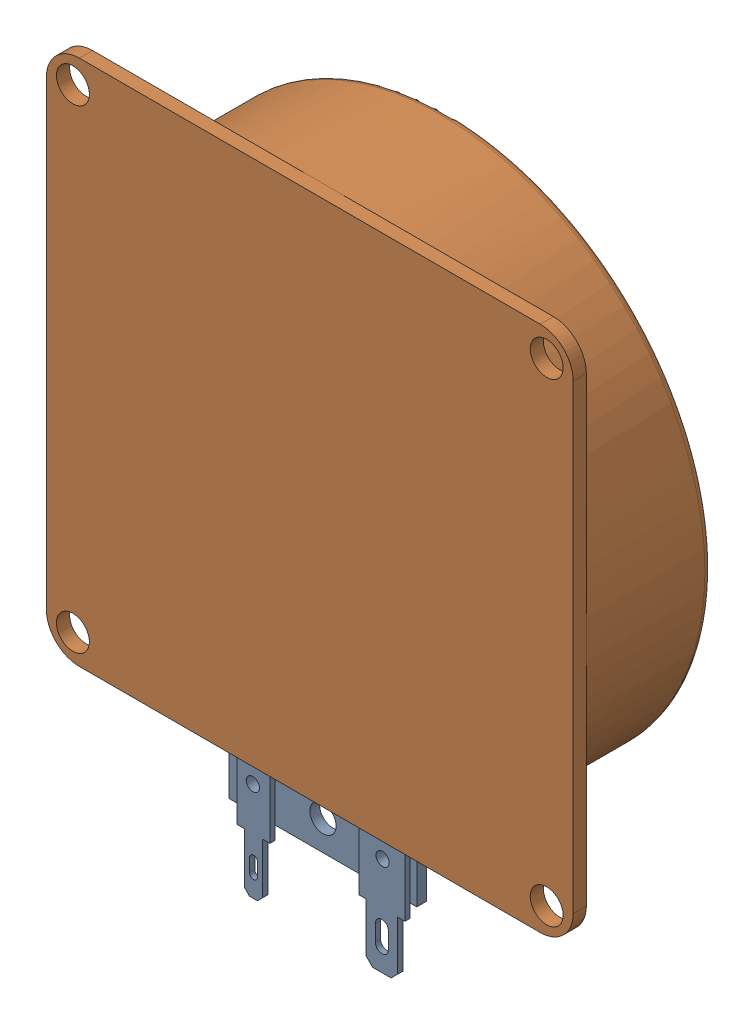
SolidWorks assembly EX 80 S, configuration Défaut. Lengths in mm.
Overall size (80 98.5 23).
2 component instances, 2 part files, 2 mates.
Components (placement in the parent):
- Fiche_Visaton_EX_80_S-1: Fiche_Visaton_EX_80_S [Défaut] at (41.1786 -10.9273 998.85) size (28.5 19.5 2.3)
- Visaton_EX_80_S-1: Visaton_EX_80_S [Défaut] at (-20.9808 65.6054 1002.35) x (-1 0 0) z (0 0 -1) size (80 80 23)
Mates (geometry in assembly coordinates):
- Coïncidente15: coincident: plane of Fiche_Visaton_EX_80_S-1 through (41.1786 19.3897 1001.15) normal (0 1 0); plane of Visaton_EX_80_S-1 through (16.7362 19.3897 1000.35) normal (0 -1 0)
- Distance2: distance = 25.75 mm aligned: plane of Fiche_Visaton_EX_80_S-1 through (-12.3644 -10.9273 1000.35) normal (1 0 0); plane of Visaton_EX_80_S-1 through (13.3856 99.3897 1000.35) normal (1 0 0)
